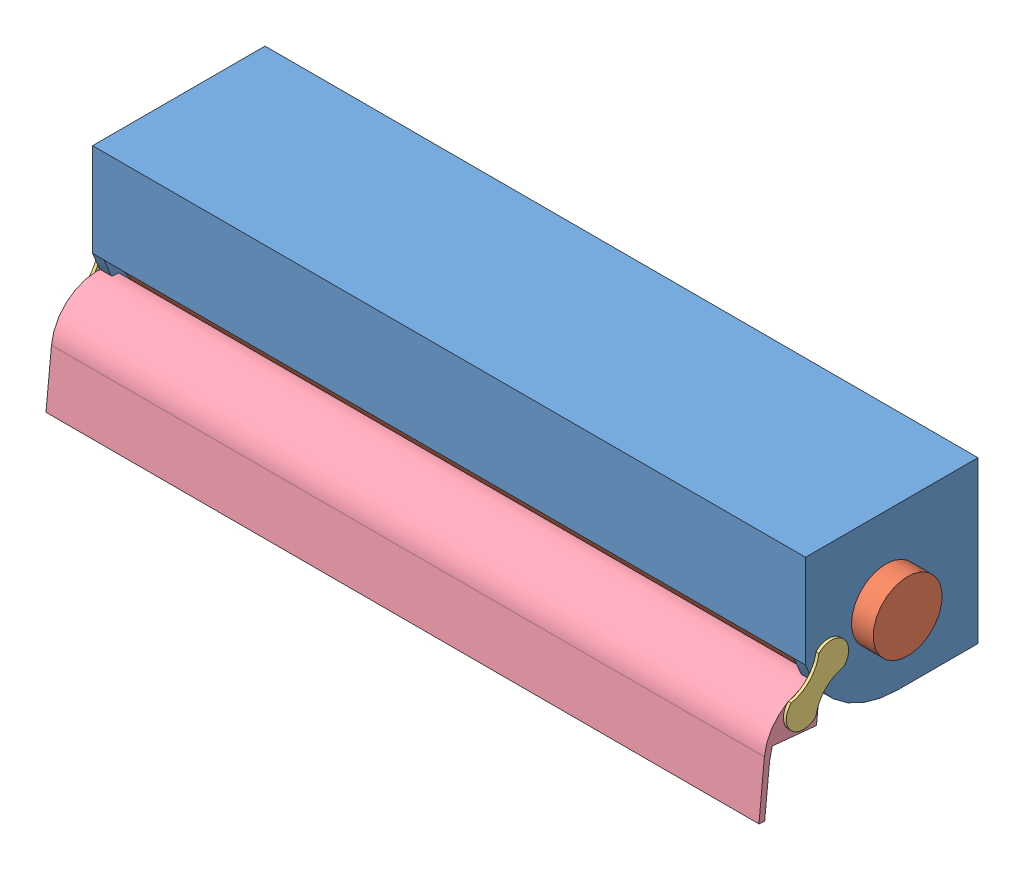
SolidWorks assembly final asmebally deployment, configuration Default. Lengths in mm.
Overall size (1676.4 506.47 495.05).
5 component instances, 4 part files, 5 mates.
Components (placement in the parent):
- holder-1: holder [Default] at (23.7573 875.8341 1469.749) size (1574.8 355.6 381)
- roll-1: roll [Default] at (-80.2046 1046.0107 1672.949) x (1 0 0) z (0 0.631823 0.775113) size (1676.4 304.8 304.8)
- dw link-1: dw link [Default] at (-26.4324 955.2258 1831.9502) x (0 0.540831 0.841131) z (-1 0 0) size (76.2 165.1 31.75)
- dw link-3: dw link [Default] at (1548.3676 962.3017 1840.9166) x (0 -0.692367 -0.721546) z (1 0 0) size (76.2 165.1 31.75)
- cover-1: cover [Default] at (1548.3676 977.4272 1817.8655) x (0 0.097837 0.995202) z (-1 0 0) size (114.3 224.55 1574.8)
Mates (geometry in assembly coordinates):
- Concentric2: concentric: cylinder of holder-1 through (1548.3676 1046.0107 1672.949) axis (-1 0 0) radius 76.2; cylinder of roll-1 through (1596.1954 1046.0107 1672.949) axis (-1 0 0) radius 76.2
- Coincident1: coincident: circle of holder-1; circle of dw link-1
- Coincident2: coincident: circle of holder-1; circle of dw link-3
- Lock1: lock: unknown of dw link-1; unknown of dw link-3
- Coincident5: coincident: circle of dw link-1; circle of cover-1
